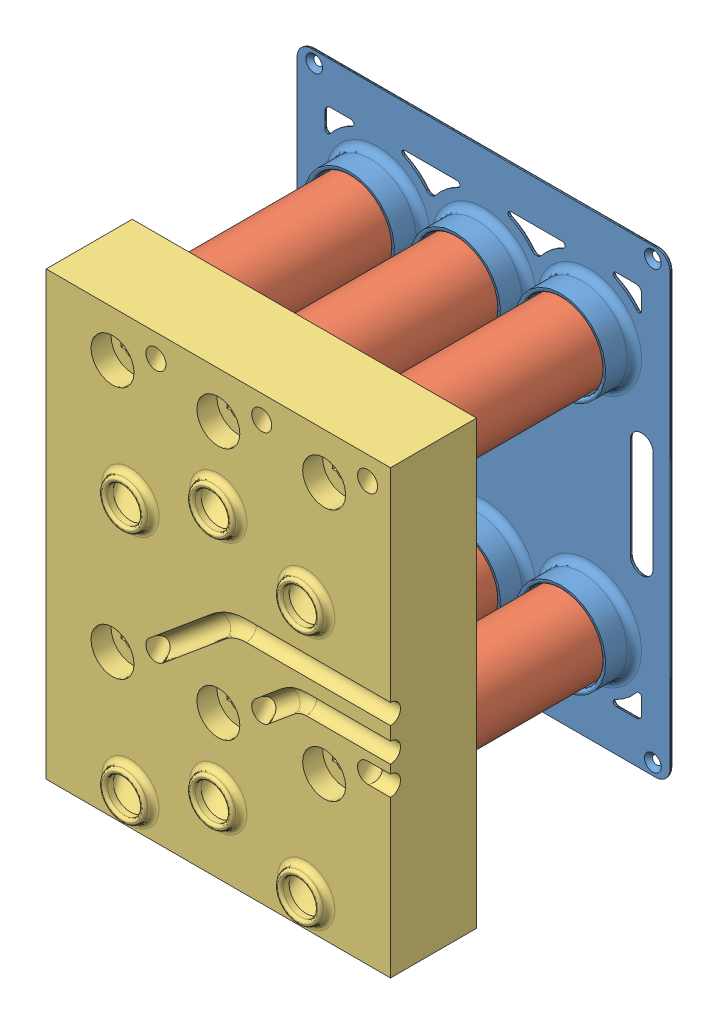
SolidWorks assembly Vial assembly, configuration Default. Lengths in mm.
Overall size (130 174.26 97).
8 component instances, 3 part files, 15 mates.
Components (placement in the parent):
- Bottom 2.0-1: Bottom 2.0 [Default] at (58 -0.0875 105.0875) x (1 0 0) z (0 -1 0) size (130 11.5 160)
- vial-1: vial [Default] at (21.1961 -44.3451 106.5875) x (1 0 0) z (0 -1 0) size (27.5 72.5 27.5)
- vial-2: vial [Default] at (58.1497 -44.3451 106.5875) x (1 0 0) z (0 -1 0) size (27.5 72.5 27.5)
- vial-3: vial [Default] at (94.8039 -44.3451 106.5875) x (1 0 0) z (0 -1 0) size (27.5 72.5 27.5)
- vial-4: vial [Default] at (21.1961 43.6549 106.5875) x (1 0 0) z (0 -1 0) size (27.5 72.5 27.5)
- vial-5: vial [Default] at (94.8039 43.6549 106.5875) x (1 0 0) z (0 -1 0) size (27.5 72.5 27.5)
- vial-6: vial [Default] at (58.1497 43.6549 106.5875) x (1 0 0) z (0 -1 0) size (27.5 72.5 27.5)
- New Top 4.0_Mirrored-1: New Top 4.0_Mirrored [Default] at (58.0761 -0.3451 169.0875) x (-1 0 0) z (0 1 0) size (120 33.9 154)
Mates (geometry in assembly coordinates):
- Coincident5: coincident anti-aligned: plane of Bottom 2.0-1 through (-2 -75.0875 106.5875) normal (0 0 1); plane of vial-1 through (21.1961 -44.3451 106.5875) normal (0 0 -1)
- Concentric7: concentric anti-aligned: circle of Bottom 2.0-1; circle of vial-1
- Coincident6: coincident anti-aligned: plane of Bottom 2.0-1 through (-2 -75.0875 106.5875) normal (0 0 1); plane of vial-2 through (58.1497 -44.3451 106.5875) normal (0 0 -1)
- Concentric8: concentric anti-aligned: circle of Bottom 2.0-1; circle of vial-2
- Coincident7: coincident anti-aligned: plane of Bottom 2.0-1 through (-2 -75.0875 106.5875) normal (0 0 1); plane of vial-3 through (94.8039 -44.3451 106.5875) normal (0 0 -1)
- Concentric9: concentric anti-aligned: circle of Bottom 2.0-1; circle of vial-3
- Coincident8: coincident anti-aligned: plane of Bottom 2.0-1 through (-2 -75.0875 106.5875) normal (0 0 1); plane of vial-4 through (21.1961 43.6549 106.5875) normal (0 0 -1)
- Coincident9: coincident anti-aligned: plane of Bottom 2.0-1 through (-2 -75.0875 106.5875) normal (0 0 1); plane of vial-5 through (94.8039 43.6549 106.5875) normal (0 0 -1)
- Coincident10: coincident anti-aligned: plane of Bottom 2.0-1 through (-2 -75.0875 106.5875) normal (0 0 1); plane of vial-6 through (58.1497 43.6549 106.5875) normal (0 0 -1)
- Concentric10: concentric anti-aligned: circle of Bottom 2.0-1; circle of vial-5
- Concentric11: concentric anti-aligned: circle of Bottom 2.0-1; circle of vial-6
- Concentric12: concentric anti-aligned: circle of Bottom 2.0-1; circle of vial-4
- Concentric14: concentric anti-aligned: circle of vial-1; circle of New Top 4.0_Mirrored-1
- Concentric15: concentric anti-aligned: circle of vial-4; circle of New Top 4.0_Mirrored-1
- Coincident15: coincident anti-aligned: circle of vial-5; plane of New Top 4.0_Mirrored-1 through (94.88 43.9125 179.0875) normal (0 0 -1)
